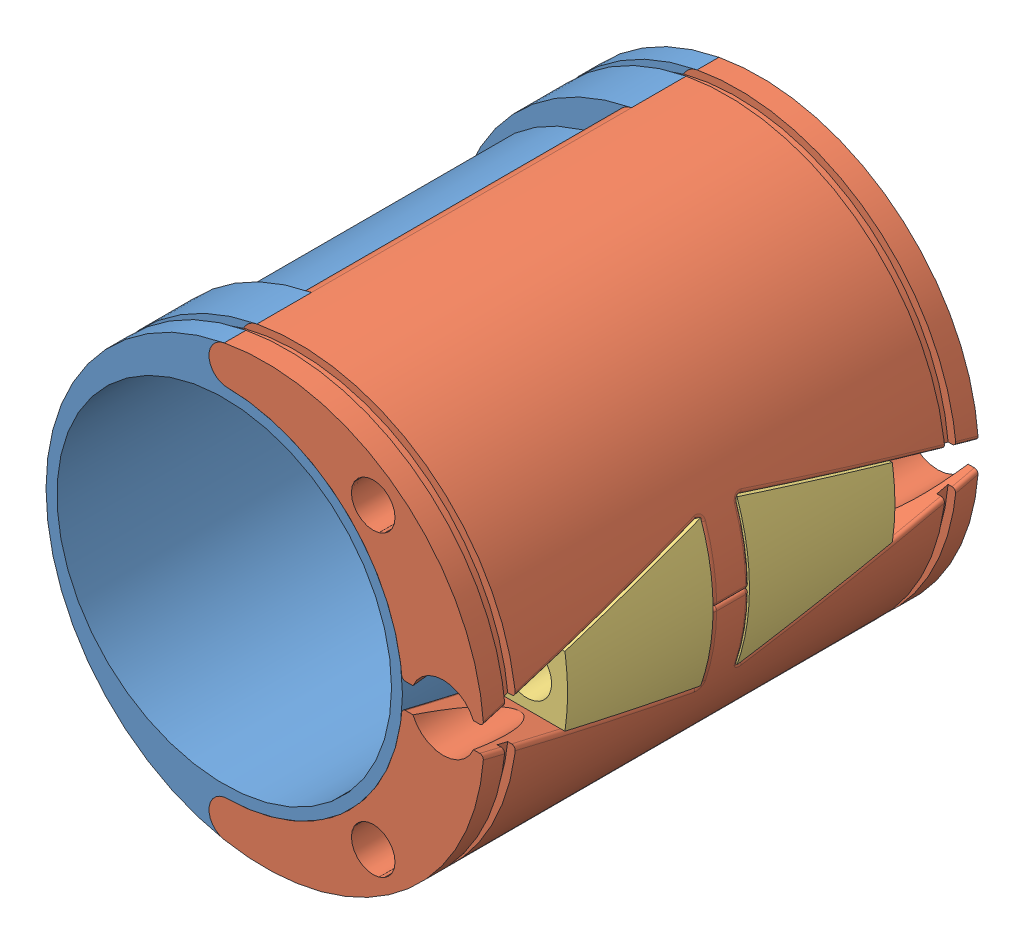
SolidWorks assembly Assemblage, configuration Default. Lengths in mm.
Overall size (182.37 126.18 68).
5 component instances, 3 part files, 9 mates.
Components (placement in the parent):
- Axe-1: Axe [Default] at (29.8297 38.4468 47.8377) size (49 59.15 68)
- coquille-1: coquille [Default] at (29.8297 38.4468 47.8377) size (37.8 30.1 68)
- coquille-2: coquille [Default] at (29.8297 38.4468 47.8377) x (1 0 0) z (0 0 -1) size (37.8 30.1 68)
- Cone de serrage-1: Cone de serrage [Default] at (59.9297 38.4468 70.3377) x (0 0 -1) z (1 0 0) size (20 100.07 182.37)
- Cone de serrage-2: Cone de serrage [Default] at (59.9297 38.4468 25.3377) x (0 0 1) z (1 0 0) size (20 100.07 182.37)
Mates (geometry in assembly coordinates):
- Coaxiale1: concentric aligned: cylinder of Axe-1 through (30.3101 11.4096 13.8377) axis (0 0 1) radius 2.5823; cylinder of coquille-1 through (30.3101 11.4096 13.8377) axis (0 0 1) radius 2.5823
- Coaxiale2: concentric anti-aligned: cylinder of Axe-1 through (30.3101 65.4841 13.8377) axis (0 0 1) radius 2.5823; cylinder of coquille-2 through (30.3101 65.4841 81.8377) axis (0 0 -1) radius 2.5823
- Coaxiale4: concentric aligned: cylinder of Axe-1 through (29.8297 38.4468 13.8377) axis (0 0 1) radius 24.5; cylinder of coquille-1 through (29.8297 38.4468 13.8377) axis (0 0 1) radius 24.5
- Coaxiale5: concentric anti-aligned: cylinder of Axe-1 through (29.8297 38.4468 13.8377) axis (0 0 1) radius 24.5; cylinder of Cone de serrage-2 through (29.8297 38.4468 45.3377) axis (0 0 -1) radius 24.5
- Coaxiale6: concentric aligned: cylinder of coquille-2 through (35.4297 38.4468 81.8377) axis (0 0 -1) radius 30.1; cylinder of Cone de serrage-2 through (35.4297 38.4468 45.3377) axis (0 0 -1) radius 30.1
- Coïncidente28: coincident anti-aligned: plane of coquille-1 through (27.7278 33.6968 25.3377) normal (0 0.967231 0.253898); plane of Cone de serrage-2 through (49.9297 33.6968 25.3377) normal (0 -0.967231 -0.253898)
- Coaxiale8: concentric aligned: cylinder of Axe-1 through (29.8297 38.4468 13.8377) axis (0 0 1) radius 24.5; cylinder of Cone de serrage-1 through (29.8297 38.4468 50.3377) axis (0 0 1) radius 24.5
- Coïncidente29: coincident aligned: plane of Axe-1 through (29.8297 38.4468 81.8377) normal (0 0 1); plane of coquille-1 through (29.8297 38.4468 81.8377) normal (0 0 1)
- Coïncidente30: coincident aligned: plane of Axe-1 through (29.8297 38.4468 81.8377) normal (0 0 1); plane of coquille-2 through (29.8297 38.4468 81.8377) normal (0 0 1)
